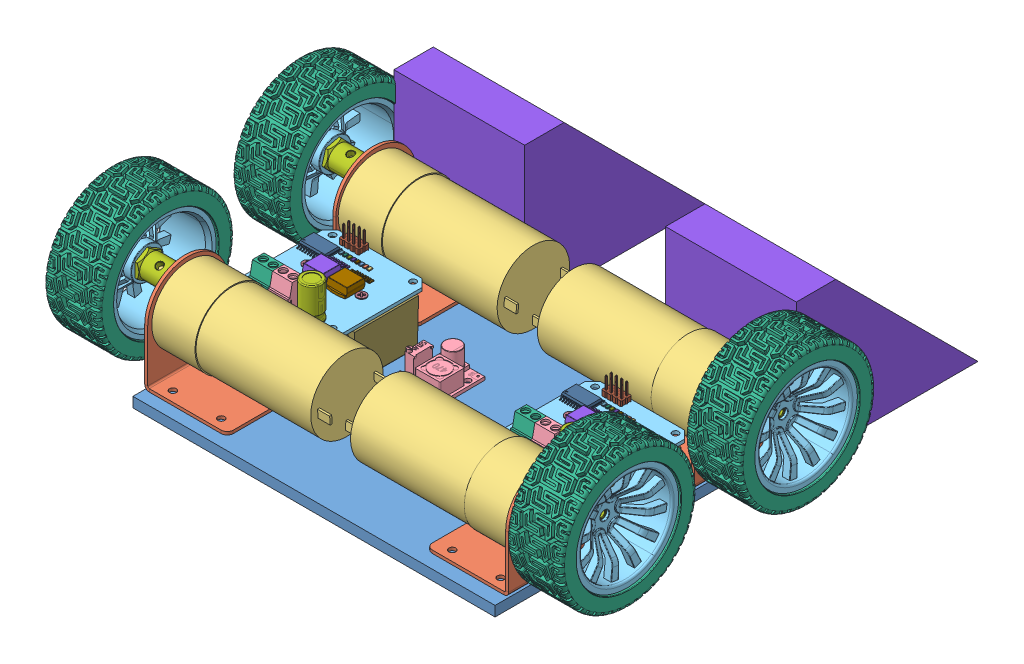
SolidWorks assembly Assembly, configuration Default. Lengths in mm.
Overall size (252.52 99.93 254.1).
71 component instances, 44 part files, 31 mates.
Components (placement in the parent):
- Base-1: Base [Default] at (142.7101 70.256 137.4346) size (180 5 160)
- 37 mm DC Geared Motor Mounting Bracket-1: 37 mm DC Geared Motor Mounting Bracket [Default] at (-11.5361 103.256 200.7248) size (41 48 40)
- 37 mm DC Geared Motor Mounting Bracket-2: 37 mm DC Geared Motor Mounting Bracket [Default] at (168.4639 103.256 199.8414) x (-1 0 0) z (0 0 -1) size (41 48 40)
- 37 mm DC Geared Motor Mounting Bracket-3: 37 mm DC Geared Motor Mounting Bracket [Default] at (-11.5361 103.256 107.2144) size (41 48 40)
- 37 mm DC Geared Motor Mounting Bracket-4: 37 mm DC Geared Motor Mounting Bracket [Default] at (168.4639 103.256 107.5491) x (-1 0 0) z (0 0 -1) size (41 48 40)
- DC Motor JS37-1: DC Motor JS37 [Default] at (145.4639 102.756 107.5491) size (105.5 37 37)
- DC Motor JS37-2: DC Motor JS37 [Default] at (145.4639 102.7792 200.4305) x (1 0 0) z (0 0.078555 0.99691) size (105.5 37 37)
- DC Motor JS37-3: DC Motor JS37 [Default] at (11.4639 102.7646 107.5729) x (-1 0 0) z (0 -0.047806 -0.998857) size (105.5 37 37)
- DC Motor JS37-4: DC Motor JS37 [Default] at (11.4639 102.7732 200.2174) x (-1 0 0) z (0 0.067653 -0.997709) size (105.5 37 37)
- BTS7960 H-Bridge Module.step-1: BTS7960 H-Bridge Module.step [Default] at (143.7139 98.156 153.4677) x (-1 0 0) z (0 1 0) size (51.5 49.91 42)
  - 2Pos Terminal Block_001.step-1: 2Pos Terminal Block_001.step [Default] at (0.8 20 1.6) x (0 1 0) z (0 0 1) size (10.01 10.41 16.8)
  - Body_001.step-1: Body_001.step [Default] at origin size (49.5 49.8 1.6)
  - 2Pos Terminal Block_002.step-1: 2Pos Terminal Block_002.step [Default] at (10.7 20 1.6) x (0 1 0) z (0 0 1) size (10.01 10.41 16.8)
  - Capacitor_001.step-1: Capacitor_001.step [Default] at (-10.7672 19.837 1.6) x (0 -1 0) z (-1 0 0) size (10.12 17.5 10.12)
  - BTN7960_001.step-1: BTN7960_001.step [Default] at (5.9321 -1.893 1.6) size (10 15.38 4.4)
  - BTN7960_002.step-1: BTN7960_002.step [Default] at (-5.9827 -1.8968 1.6) size (10 15.38 4.4)
  - SOJ 20_001.step-1: SOJ 20_001.step [Default] at (17.2939 -12.0721 1.6) x (0 -1 0) z (0 0 1) size (10.85 12.9 2.4)
  - 2x4 Male Header_001.step-1: 2x4 Male Header_001.step [Default] at (5.8669 -22.8725 1.6) size (10.16 5.08 11.3)
  - Fillet.step-1: Fillet.step [Default] at origin size (51.5 31.77 22.9)
  - M2.5x6-Screw.step-1: M2.5x6-Screw.step [Default] at (-13.3 -2.4 2) size (4.5 4.5 6)
  - M2.5x6-Screw.step-2: M2.5x6-Screw.step [Default] at (13.7 -2.4 2) size (4.5 4.5 6)
  - 0805 Resistor_001.step-1: 0805 Resistor_001.step [Default] at (9.9588 -15.7217 1.6) x (0 -1 0) z (0 0 1) size (2 1.25 0.5)
  - 0805 Resistor_002.step-1: 0805 Resistor_002.step [Default] at (7.9588 -15.7217 1.6) x (0 -1 0) z (0 0 1) size (2 1.25 0.5)
  - 0805 Resistor_003.step-1: 0805 Resistor_003.step [Default] at (5.9588 -15.7217 1.6) x (0 -1 0) z (0 0 1) size (2 1.25 0.5)
  - 0805 Resistor_004.step-1: 0805 Resistor_004.step [Default] at (3.9588 -15.7217 1.6) x (0 -1 0) z (0 0 1) size (2 1.25 0.5)
  - 0805 Resistor_005.step-1: 0805 Resistor_005.step [Default] at (1.9588 -15.7217 1.6) x (0 -1 0) z (0 0 1) size (2 1.25 0.5)
  - 0805 Resistor_006.step-1: 0805 Resistor_006.step [Default] at (-0.0412 -15.7217 1.6) x (0 -1 0) z (0 0 1) size (2 1.25 0.5)
  - 0805 Resistor_007.step-1: 0805 Resistor_007.step [Default] at (-2.0412 -15.7217 1.6) x (0 -1 0) z (0 0 1) size (2 1.25 0.5)
  - 0805 Resistor_008.step-1: 0805 Resistor_008.step [Default] at (-4.0412 -15.7217 1.6) x (0 -1 0) z (0 0 1) size (2 1.25 0.5)
- BTS7960 H-Bridge Module.step-2: BTS7960 H-Bridge Module.step [Default] at (13.2139 98.156 153.4124) x (-1 0 0) z (0 1 0) size (51.5 49.91 42)
  - 2Pos Terminal Block_001.step-1: 2Pos Terminal Block_001.step [Default] at (0.8 20 1.6) x (0 1 0) z (0 0 1) size (10.01 10.41 16.8)
  - Body_001.step-1: Body_001.step [Default] at origin size (49.5 49.8 1.6)
  - 2Pos Terminal Block_002.step-1: 2Pos Terminal Block_002.step [Default] at (10.7 20 1.6) x (0 1 0) z (0 0 1) size (10.01 10.41 16.8)
  - Capacitor_001.step-1: Capacitor_001.step [Default] at (-10.7672 19.837 1.6) x (0 -1 0) z (-1 0 0) size (10.12 17.5 10.12)
  - BTN7960_001.step-1: BTN7960_001.step [Default] at (5.9321 -1.893 1.6) size (10 15.38 4.4)
  - BTN7960_002.step-1: BTN7960_002.step [Default] at (-5.9827 -1.8968 1.6) size (10 15.38 4.4)
  - SOJ 20_001.step-1: SOJ 20_001.step [Default] at (17.2939 -12.0721 1.6) x (0 -1 0) z (0 0 1) size (10.85 12.9 2.4)
  - 2x4 Male Header_001.step-1: 2x4 Male Header_001.step [Default] at (5.8669 -22.8725 1.6) size (10.16 5.08 11.3)
  - Fillet.step-1: Fillet.step [Default] at origin size (51.5 31.77 22.9)
  - M2.5x6-Screw.step-1: M2.5x6-Screw.step [Default] at (-13.3 -2.4 2) size (4.5 4.5 6)
  - M2.5x6-Screw.step-2: M2.5x6-Screw.step [Default] at (13.7 -2.4 2) size (4.5 4.5 6)
  - 0805 Resistor_001.step-1: 0805 Resistor_001.step [Default] at (9.9588 -15.7217 1.6) x (0 -1 0) z (0 0 1) size (2 1.25 0.5)
  - 0805 Resistor_002.step-1: 0805 Resistor_002.step [Default] at (7.9588 -15.7217 1.6) x (0 -1 0) z (0 0 1) size (2 1.25 0.5)
  - 0805 Resistor_003.step-1: 0805 Resistor_003.step [Default] at (5.9588 -15.7217 1.6) x (0 -1 0) z (0 0 1) size (2 1.25 0.5)
  - 0805 Resistor_004.step-1: 0805 Resistor_004.step [Default] at (3.9588 -15.7217 1.6) x (0 -1 0) z (0 0 1) size (2 1.25 0.5)
  - 0805 Resistor_005.step-1: 0805 Resistor_005.step [Default] at (1.9588 -15.7217 1.6) x (0 -1 0) z (0 0 1) size (2 1.25 0.5)
  - 0805 Resistor_006.step-1: 0805 Resistor_006.step [Default] at (-0.0412 -15.7217 1.6) x (0 -1 0) z (0 0 1) size (2 1.25 0.5)
  - 0805 Resistor_007.step-1: 0805 Resistor_007.step [Default] at (-2.0412 -15.7217 1.6) x (0 -1 0) z (0 0 1) size (2 1.25 0.5)
  - 0805 Resistor_008.step-1: 0805 Resistor_008.step [Default] at (-4.0412 -15.7217 1.6) x (0 -1 0) z (0 0 1) size (2 1.25 0.5)
- LM2596_Buck_Converter.stp-1: LM2596_Buck_Converter.stp [Default] at (47.8425 75.256 132.4261) x (0.010099 0 0.999949) z (-0.999949 0 0.010099) size (43 14 21.15)
- 65mmwheel-1: 65mmwheel [Default] at (191.2139 110.256 107.5491) size (31.76 86.61 86.6)
  - 65mmÝrnÎ;Å-žE_„68mm.STEP-1: 65mmÝrnÎ;Å-žE_„68mm.STEP [Default] at origin size (31.76 86.61 86.6)
    - ________.STEP-1: ________.STEP [Default] x (1 0 0) z (0 0.808864 0.587995) size (25 51.5 51.5)
    - ____.STEP-1: ____.STEP [Default] x (1 0 0) z (0 0.328458 0.944518) size (27.02 68.04 68.02)
    - 3MM______.STEP-1: 3MM______.STEP [Default] x (0 0.808864 0.587995) z (-1 0 0) size (13.83 12.01 18.25)
- 65mmwheel-2: 65mmwheel [Default] at (191.2139 110.9638 196.3304) size (31.76 86.61 86.6)
  - 65mmÝrnÎ;Å-žE_„68mm.STEP-1: 65mmÝrnÎ;Å-žE_„68mm.STEP [Default] at origin size (31.76 86.61 86.6)
    - ________.STEP-1: ________.STEP [Default] x (1 0 0) z (0 0.808864 0.587995) size (25 51.5 51.5)
    - ____.STEP-1: ____.STEP [Default] x (1 0 0) z (0 0.328458 0.944518) size (27.02 68.04 68.02)
    - 3MM______.STEP-1: 3MM______.STEP [Default] x (0 0.808864 0.587995) z (-1 0 0) size (13.83 12.01 18.25)
- 65mmwheel-3: 65mmwheel [Default] at (-34.2861 110.256 107.2144) x (-1 0 0) z (0 0.644253 0.764812) size (31.76 86.61 86.6)
  - 65mmÝrnÎ;Å-žE_„68mm.STEP-1: 65mmÝrnÎ;Å-žE_„68mm.STEP [Default] at origin size (31.76 86.61 86.6)
    - ________.STEP-1: ________.STEP [Default] x (1 0 0) z (0 0.808864 0.587995) size (25 51.5 51.5)
    - ____.STEP-1: ____.STEP [Default] x (1 0 0) z (0 0.328458 0.944518) size (27.02 68.04 68.02)
    - 3MM______.STEP-1: 3MM______.STEP [Default] x (0 0.808864 0.587995) z (-1 0 0) size (13.83 12.01 18.25)
- 65mmwheel-4: 65mmwheel [Default] at (-34.2861 110.256 200.7248) x (-1 0 0) z (0 0.403224 0.915101) size (31.76 86.61 86.6)
  - 65mmÝrnÎ;Å-žE_„68mm.STEP-1: 65mmÝrnÎ;Å-žE_„68mm.STEP [Default] at origin size (31.76 86.61 86.6)
    - ________.STEP-1: ________.STEP [Default] x (1 0 0) z (0 0.808864 0.587995) size (25 51.5 51.5)
    - ____.STEP-1: ____.STEP [Default] x (1 0 0) z (0 0.328458 0.944518) size (27.02 68.04 68.02)
    - 3MM______.STEP-1: 3MM______.STEP [Default] x (0 0.808864 0.587995) z (-1 0 0) size (13.83 12.01 18.25)
- Bracket-1: Bracket [Default] at (178.4639 101.0107 88.8923) x (-1 0 0) z (0 0 -1) size (200 70.71 90.3)
Mates (geometry in assembly coordinates):
- Coincident1: coincident aligned: plane of Base-1 through (-11.5361 75.256 66.6038) normal (-1 0 0); plane of 37 mm DC Geared Motor Mounting Bracket-1 through (-11.5361 103.256 200.7248) normal (-1 0 0)
- Coincident3: coincident anti-aligned: plane of Base-1 through (142.7101 75.256 137.4346) normal (0 1 0); plane of 37 mm DC Geared Motor Mounting Bracket-1 through (-10.0361 75.256 220.7248) normal (0 -1 0)
- Coincident4: coincident aligned: plane of Base-1 through (168.4639 75.256 226.6038) normal (1 0 0); plane of 37 mm DC Geared Motor Mounting Bracket-2 through (168.4639 103.256 199.8414) normal (1 0 0)
- Coincident6: coincident anti-aligned: plane of Base-1 through (142.7101 75.256 137.4346) normal (0 1 0); plane of 37 mm DC Geared Motor Mounting Bracket-2 through (166.9639 75.256 179.8414) normal (0 -1 0)
- Coincident7: coincident aligned: plane of Base-1 through (-11.5361 75.256 66.6038) normal (-1 0 0); plane of 37 mm DC Geared Motor Mounting Bracket-3 through (-11.5361 103.256 107.2144) normal (-1 0 0)
- Coincident8: coincident anti-aligned: plane of Base-1 through (142.7101 75.256 137.4346) normal (0 1 0); plane of 37 mm DC Geared Motor Mounting Bracket-3 through (-10.0361 75.256 127.2144) normal (0 -1 0)
- Coincident9: coincident aligned: plane of Base-1 through (168.4639 75.256 226.6038) normal (1 0 0); plane of 37 mm DC Geared Motor Mounting Bracket-4 through (168.4639 103.256 107.5491) normal (1 0 0)
- Coincident10: coincident anti-aligned: plane of Base-1 through (142.7101 75.256 137.4346) normal (0 1 0); plane of 37 mm DC Geared Motor Mounting Bracket-4 through (166.9639 75.256 87.5491) normal (0 -1 0)
- Coincident11: coincident anti-aligned: plane of 37 mm DC Geared Motor Mounting Bracket-1 through (-10.0361 103.256 200.7248) normal (1 0 0); plane of DC Motor JS37-4 through (-10.0361 102.7732 200.2174) normal (-1 0 0)
- Coincident12: coincident anti-aligned: plane of 37 mm DC Geared Motor Mounting Bracket-3 through (-10.0361 103.256 107.2144) normal (1 0 0); plane of DC Motor JS37-3 through (-10.0361 102.7646 107.5729) normal (-1 0 0)
- Coincident13: coincident anti-aligned: plane of 37 mm DC Geared Motor Mounting Bracket-2 through (166.9639 103.256 199.8414) normal (-1 0 0); plane of DC Motor JS37-2 through (166.9639 102.7792 200.4305) normal (1 0 0)
- Coincident14: coincident anti-aligned: plane of 37 mm DC Geared Motor Mounting Bracket-4 through (166.9639 103.256 107.5491) normal (-1 0 0); plane of DC Motor JS37-1 through (166.9639 102.756 107.5491) normal (1 0 0)
- Concentric1: concentric aligned: circle of 37 mm DC Geared Motor Mounting Bracket-1; circle of DC Motor JS37-4
- Concentric2: concentric aligned: circle of 37 mm DC Geared Motor Mounting Bracket-3; circle of DC Motor JS37-3
- Concentric3: concentric aligned: circle of 37 mm DC Geared Motor Mounting Bracket-2; circle of DC Motor JS37-2
- Concentric4: concentric aligned: circle of 37 mm DC Geared Motor Mounting Bracket-4; circle of DC Motor JS37-1
- Coincident15: coincident anti-aligned: plane of Base-1 through (142.7101 75.256 137.4346) normal (0 1 0); plane of BTS7960 H-Bridge Module.step-1/Fillet.step-1 through (143.7139 75.256 151.0677) normal (0 -1 0)
- Coincident16: coincident aligned: plane of Base-1 through (168.4639 75.256 226.6038) normal (1 0 0); plane of BTS7960 H-Bridge Module.step-1/Body_001.step-1 through (168.4639 98.156 128.5677) normal (1 0 0)
- Coincident17: coincident anti-aligned: plane of Base-1 through (142.7101 75.256 137.4346) normal (0 1 0); plane of BTS7960 H-Bridge Module.step-2/Fillet.step-1 through (13.2139 75.256 151.0124) normal (0 -1 0)
- Coincident18: coincident aligned: plane of Base-1 through (-11.5361 75.256 66.6038) normal (-1 0 0); plane of BTS7960 H-Bridge Module.step-2/Body_001.step-1 through (-11.5361 98.156 178.3124) normal (-1 0 0)
- Coincident19: coincident anti-aligned: plane of Base-1 through (142.7101 75.256 137.4346) normal (0 1 0); plane of LM2596_Buck_Converter.stp-1 through (58.6341 75.256 153.8182) normal (0 -1 0)
- Concentric5: concentric anti-aligned: circle of DC Motor JS37-1; circle of 65mmwheel-1/65mmÝrnÎ;Å-žE_„68mm.STEP-1/3MM______.STEP-1
- Coincident21: coincident anti-aligned: plane of DC Motor JS37-1 through (172.9639 102.756 107.5491) normal (1 0 0); plane of 65mmwheel-1/65mmÝrnÎ;Å-žE_„68mm.STEP-1/3MM______.STEP-1 through (172.9639 115.7666 111.555) normal (-1 0 0)
- Coincident22: coincident anti-aligned: plane of DC Motor JS37-2 through (172.9639 102.7792 200.4305) normal (1 0 0); plane of 65mmwheel-2/65mmÝrnÎ;Å-žE_„68mm.STEP-1/3MM______.STEP-1 through (172.9639 116.4744 200.3363) normal (-1 0 0)
- Concentric6: concentric anti-aligned: circle of DC Motor JS37-4; circle of 65mmwheel-4/65mmÝrnÎ;Å-žE_„68mm.STEP-1/3MM______.STEP-1
- Coincident23: coincident anti-aligned: plane of DC Motor JS37-4 through (-16.0361 102.7732 200.2174) normal (-1 0 0); plane of 65mmwheel-4/65mmÝrnÎ;Å-žE_„68mm.STEP-1/3MM______.STEP-1 through (-16.0361 106.8285 206.6125) normal (1 0 0)
- Concentric7: concentric anti-aligned: circle of DC Motor JS37-3; circle of 65mmwheel-3/65mmÝrnÎ;Å-žE_„68mm.STEP-1/3MM______.STEP-1
- Coincident24: coincident anti-aligned: plane of DC Motor JS37-3 through (-16.0361 102.7646 107.5729) normal (-1 0 0); plane of 65mmwheel-3/65mmÝrnÎ;Å-žE_„68mm.STEP-1/3MM______.STEP-1 through (-16.0361 108.6222 113.8283) normal (1 0 0)
- Coincident28: coincident: plane of Base-1 through (142.7101 70.256 137.4346) normal (0 -1 0); plane of Bracket-1 through (4.4733 70.256 -3.3962) normal (0 -1 0)
- Coincident29: coincident: plane of Base-1 through (168.4639 75.256 66.6038) normal (0 0 -1); plane of Bracket-1 through (4.4733 70.256 66.6038) normal (0 0 1)
- Coincident30: coincident aligned: plane of Base-1 through (113.4639 75.256 66.6038) normal (-1 0 0); plane of Bracket-1 through (139.4733 -97.0298 86.9038) normal (-1 0 0)
